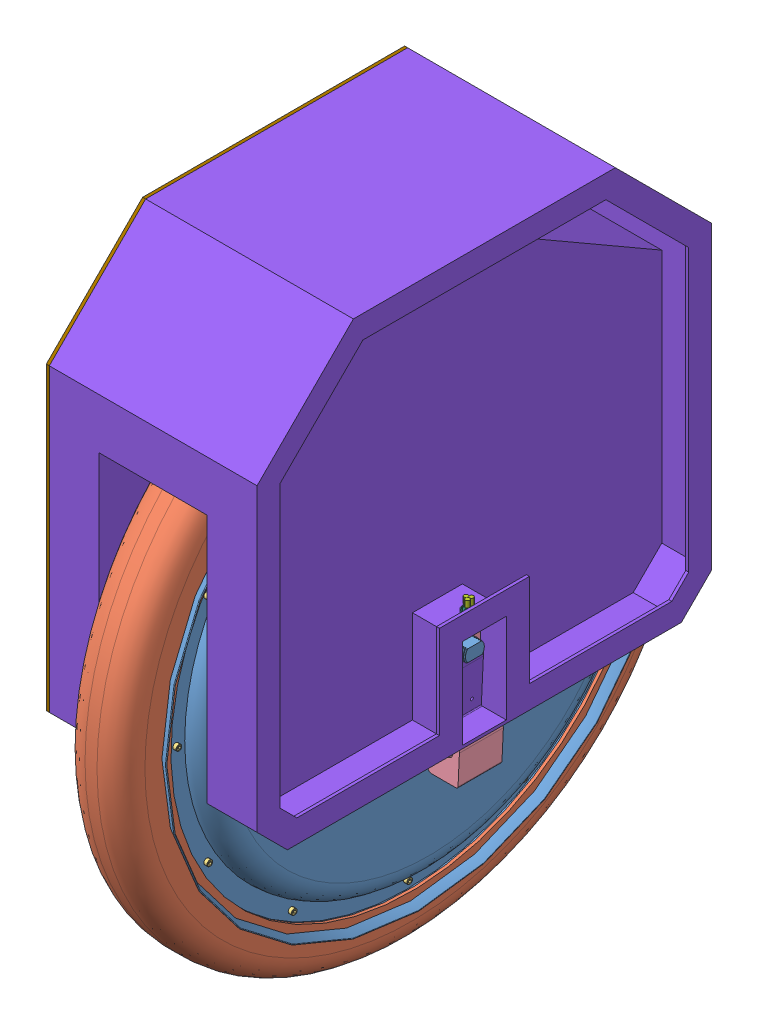
SolidWorks assembly euc0.5, configuration Default. Lengths in mm.
Overall size (364.75 810.04 810.04).
40 component instances, 14 part files, 56 mates.
Components (placement in the parent):
- wheel-1: wheel [Default] at origin size (217.51 810.04 810.04)
  - motor-1: motor [Default] at origin size (188.73 505.83 505.83)
  - tyre-1: tyre [Default] at (-29.8207 0 0) x (1 0 0) z (0 0.587098 0.809516) size (60 580 580)
  - socket head cap screw_ai-1: socket head cap screw_ai [HX-SHCS 0.138-40x0.188x0.188-N] at (29.5052 231 0) x (-1 0 0) z (0 0 -1) size (8.28 5.74 5.74)
  - socket head cap screw_ai-2: socket head cap screw_ai [HX-SHCS 0.138-40x0.188x0.188-N] at (29.5052 200.0519 -115.5) x (-1 0 0) z (0 -0.5 -0.866025) size (8.28 5.74 5.74)
  - socket head cap screw_ai-3: socket head cap screw_ai [HX-SHCS 0.138-40x0.188x0.188-N] at (29.5052 200.0519 115.5) x (-1 0 0) z (0 0.5 -0.866025) size (8.28 5.74 5.74)
  - socket head cap screw_ai-4: socket head cap screw_ai [HX-SHCS 0.138-40x0.188x0.188-N] at (29.5052 115.5 200.0519) x (-1 0 0) z (0 0.866025 -0.5) size (8.28 5.74 5.74)
  - socket head cap screw_ai-5: socket head cap screw_ai [HX-SHCS 0.138-40x0.188x0.188-N] at (29.5052 0 231) x (-1 0 0) z (0 1 0) size (8.28 5.74 5.74)
  - socket head cap screw_ai-6: socket head cap screw_ai [HX-SHCS 0.138-40x0.188x0.188-N] at (29.5052 -115.5 200.0519) x (-1 0 0) z (0 0.866025 0.5) size (8.28 5.74 5.74)
  - socket head cap screw_ai-7: socket head cap screw_ai [HX-SHCS 0.138-40x0.188x0.188-N] at (29.5052 -200.0519 115.5) x (-1 0 0) z (0 0.5 0.866025) size (8.28 5.74 5.74)
  - socket head cap screw_ai-8: socket head cap screw_ai [HX-SHCS 0.138-40x0.188x0.188-N] at (29.5052 -231 0) x (-1 0 0) z (0 0 1) size (8.28 5.74 5.74)
  - socket head cap screw_ai-9: socket head cap screw_ai [HX-SHCS 0.138-40x0.188x0.188-N] at (29.5052 -200.0519 -115.5) x (-1 0 0) z (0 -0.5 0.866025) size (8.28 5.74 5.74)
  - socket head cap screw_ai-10: socket head cap screw_ai [HX-SHCS 0.138-40x0.188x0.188-N] at (29.5052 -115.5 -200.0519) x (-1 0 0) z (0 -0.866025 0.5) size (8.28 5.74 5.74)
  - socket head cap screw_ai-11: socket head cap screw_ai [HX-SHCS 0.138-40x0.188x0.188-N] at (29.5052 0 -231) x (-1 0 0) z (0 -1 0) size (8.28 5.74 5.74)
  - socket head cap screw_ai-12: socket head cap screw_ai [HX-SHCS 0.138-40x0.188x0.188-N] at (29.5052 115.5 -200.0519) x (-1 0 0) z (0 -0.866025 -0.5) size (8.28 5.74 5.74)
  - socket head cap screw_ai-13: socket head cap screw_ai [HX-SHCS 0.138-40x0.188x0.188-N] at (-29.5052 231 0) size (8.28 5.74 5.74)
  - socket head cap screw_ai-14: socket head cap screw_ai [HX-SHCS 0.138-40x0.188x0.188-N] at (-29.5052 200.0519 -115.5) x (1 0 0) z (0 0.5 0.866025) size (8.28 5.74 5.74)
  - socket head cap screw_ai-15: socket head cap screw_ai [HX-SHCS 0.138-40x0.188x0.188-N] at (-29.5052 200.0519 115.5) x (1 0 0) z (0 -0.5 0.866025) size (8.28 5.74 5.74)
  - socket head cap screw_ai-16: socket head cap screw_ai [HX-SHCS 0.138-40x0.188x0.188-N] at (-29.5052 115.5 200.0519) x (1 0 0) z (0 -0.866025 0.5) size (8.28 5.74 5.74)
  - socket head cap screw_ai-17: socket head cap screw_ai [HX-SHCS 0.138-40x0.188x0.188-N] at (-29.5052 0 231) x (1 0 0) z (0 -1 0) size (8.28 5.74 5.74)
  - socket head cap screw_ai-18: socket head cap screw_ai [HX-SHCS 0.138-40x0.188x0.188-N] at (-29.5052 -115.5 200.0519) x (1 0 0) z (0 -0.866025 -0.5) size (8.28 5.74 5.74)
  - socket head cap screw_ai-19: socket head cap screw_ai [HX-SHCS 0.138-40x0.188x0.188-N] at (-29.5052 -200.0519 115.5) x (1 0 0) z (0 -0.5 -0.866025) size (8.28 5.74 5.74)
  - socket head cap screw_ai-20: socket head cap screw_ai [HX-SHCS 0.138-40x0.188x0.188-N] at (-29.5052 -231 0) x (1 0 0) z (0 0 -1) size (8.28 5.74 5.74)
  - socket head cap screw_ai-21: socket head cap screw_ai [HX-SHCS 0.138-40x0.188x0.188-N] at (-29.5052 -200.0519 -115.5) x (1 0 0) z (0 0.5 -0.866025) size (8.28 5.74 5.74)
  - socket head cap screw_ai-22: socket head cap screw_ai [HX-SHCS 0.138-40x0.188x0.188-N] at (-29.5052 -115.5 -200.0519) x (1 0 0) z (0 0.866025 -0.5) size (8.28 5.74 5.74)
  - socket head cap screw_ai-23: socket head cap screw_ai [HX-SHCS 0.138-40x0.188x0.188-N] at (-29.5052 0 -231) x (1 0 0) z (0 1 0) size (8.28 5.74 5.74)
  - socket head cap screw_ai-24: socket head cap screw_ai [HX-SHCS 0.138-40x0.188x0.188-N] at (-29.5052 115.5 -200.0519) x (1 0 0) z (0 0.866025 0.5) size (8.28 5.74 5.74)
  - pedal hanger1-1: pedal hanger1 [Default] at (128.9328 -140.4403 -75.0082) x (0.997537 -0.070149 0) z (-0.006861 -0.09757 0.995205) size (54.31 133.41 56.48)
  - pedal hanger2-1: pedal hanger2 [Default] at (-128.9328 -140.4403 75.0082) x (-0.997537 -0.070149 0) z (0.006861 -0.09757 -0.995205) size (54.31 133.41 56.48)
- mt60 fem-1: mt60 fem [Default] at (85.5155 -2.714 -4.2673) x (0 1 0) z (0.866025 0 -0.5) size (29 12 12.94)
  - Мама^mt60 fem-1: Мама^mt60 fem [По умолчанию] at (18.214 0 0) x (0 0 -1) z (1 0 0) size (12.94 12 20) (virtual)
  - Колпачек 2^mt60 fem-1: Колпачек 2^mt60 fem [По умолчанию] at (35.714 0 0) x (0 0 -1) z (1 0 0) size (12.94 12 13) (hidden, virtual)
  - Деталь11^mt60 fem-1: Деталь11^mt60 fem [По умолчанию] at (44.714 0 0) x (0 0 -1) z (1 0 0) size (8 7.46 6.5) (virtual)
- Battery-1: Battery [Default] at (75 -47.6654 124.2759) x (0 0 -1) z (1 0 0) size (162 240 36) (hidden)
- Battery2-1: Battery2 [Default] at (75 -56.177 -111.8756) x (0 0 -1) z (1 0 0) size (162 260 36) (hidden)
- Battery3-1: Battery3 [Default] at (-206.3607 -72.6948 -163.7053) x (0 0 -1) z (1 0 0) size (162 260 36) (hidden)
- Battery4-1: Battery4 [Default] at (-186.6008 -70.2528 81.2406) x (0 0 -1) z (1 0 0) size (162 260 36) (hidden)
- Chassis^euc0.5-5: Chassis^euc0.5 [Default] at (48 0 0) x (0 0 -1) z (1 0 0) size (455.15 427.31 208) (virtual)
- Lid^euc0.5-3: Lid^euc0.5 [Default] at (104 0 0) x (0 0 -1) z (1 0 0) size (455.15 427.31 3) (hidden, virtual)
- Lid^euc0.5-4: Lid^euc0.5 [Default] at (-104 0 0) x (0 0 1) z (-1 0 0) size (455.15 427.31 3) (virtual)
Mates (geometry in assembly coordinates):
- Parallel1: parallel anti-aligned: plane of Chassis-1/Internal chassis-1 through (0 28 0) normal (0 1 0); plane of mt60 fem-1/Copy of Мама^mt60 fem-1 through (90.0311 15.5 3.5538) normal (0 -1 0)
- Parallel2: parallel aligned: plane of Chassis-1/Internal chassis-1 through (57 28 288) normal (1 0 0); plane of mt60 fem-1/Copy of Мама^mt60 fem-1 through (93 29 3.5538) normal (1 0 0)
- Coincident3: coincident anti-aligned: plane of Chassis-1/Internal chassis-1 through (93 7.266 3.5) normal (-1 0 0); plane of mt60 fem-1/Copy of Мама^mt60 fem-1 through (93 29 3.5538) normal (1 0 0)
- Coincident4: coincident anti-aligned: plane of Chassis-1/Internal chassis-1 through (82.4378 7.266 2.5981) normal (0.5 0 -0.866025); plane of mt60 fem-1/Copy of Мама^mt60 fem-1 through (82.4845 29 2.625) normal (-0.5 0 0.866025)
- Coincident5: coincident aligned: plane of Chassis-1/Internal chassis-1 through (100 25 0) normal (0 -1 0); plane of mt60 fem-1/Copy of Мама^mt60 fem-1 through (83.9689 25 0.0538) normal (0 -1 0)
- Coincident18: coincident anti-aligned: plane of Chassis-1/Internal chassis-1 through (57 28 288) normal (1 0 0); plane of Battery1-1 through (57 187.8877 190.3024) normal (-1 0 0)
- Coincident23: coincident anti-aligned: plane of Chassis-1/Internal chassis-1 through (57 28 288) normal (1 0 0); plane of Battery2-2 through (57 212.7697 -24.9641) normal (-1 0 0)
- Parallel5: parallel aligned: plane of Chassis-1/Internal chassis-1 through (0 28 0) normal (0 1 0); plane of Battery1-1 through (75 187.8877 109.3024) normal (0 1 0)
- Parallel6: parallel aligned: plane of Chassis-1/Internal chassis-1 through (0 28 0) normal (0 1 0); plane of Battery2-2 through (75 212.7697 -105.9641) normal (0 1 0)
- InPlace2: in place: plane of wheel-1/motor-1 through (57 28 288) normal (1 0 0); plane of ? through (57 0 0) normal (1 0 0); moOrthogonalPlaneRef_w of wheel-1/motor-1 through (57 28 288) normal (1 0 0); plane of ? through (57 0 0) normal (0 1 0); plane of wheel-1/motor-1 through (57 28 288) normal (1 0 0); plane of ? through (57 0 0) normal (0 0 -1); plane of wheel-1/motor-1 through (57 28 288) normal (1 0 0); unknown of ?
- Coincident26: coincident aligned: plane of ?; plane of ?
- Coincident27: coincident aligned: moOrthogonalPlaneRef_w of Chassis-1/Internal chassis-1 through (57 0 0) normal (0 1 0); plane of Lid^euc0.2-2 through (57 0 0) normal (0 1 0)
- Coincident28: coincident anti-aligned: moOrthogonalPlaneRef_w of Chassis-1/Internal chassis-1 through (57 0 0) normal (0 0 1); plane of Lid^euc0.2-2 through (57 0 0) normal (0 0 -1)
- InPlace3: in place: plane of wheel-1/motor-1 through (0 303.0294 0) normal (0 1 0); plane of ? through (0 303.0294 0) normal (0 1 0); plane of wheel-1/motor-1 through (0 303.0294 0) normal (0 1 0); plane of ? through (0 303.0294 0) normal (0 0 -1); plane of wheel-1/motor-1 through (0 303.0294 0) normal (0 1 0); plane of ? through (0 303.0294 0) normal (1 0 0); plane of wheel-1/motor-1 through (0 303.0294 0) normal (0 1 0); unknown of ?
- Coincident1482: coincident aligned: plane of ?; plane of ?
- Coincident1483: coincident aligned: moOrthogonalPlaneRef_w of top chassis^euc0.2-1 through (0 303.0294 0) normal (0 0 -1); plane of Pcb plate^euc0.2-1 through (0 303.0294 0) normal (0 0 -1)
- Coincident1484: coincident anti-aligned: moOrthogonalPlaneRef_w of top chassis^euc0.2-1 through (0 303.0294 0) normal (-1 0 0); plane of Pcb plate^euc0.2-1 through (0 303.0294 0) normal (1 0 0)
- Coincident1488: coincident anti-aligned: plane of Pcb plate^euc0.2-1 through (-24 312.0294 76) normal (0 1 0); plane of pcb^euc0.2-1 through (0 312.0294 0) normal (0 -1 0)
- Coincident1489: coincident aligned: plane of Pcb plate^euc0.2-1 through (-40 307.0294 80) normal (0 0 1); plane of pcb^euc0.2-1 through (-28 315.0294 80) normal (0 0 1)
- Coincident1490: coincident anti-aligned: plane of Pcb plate^euc0.2-1 through (28 315.0294 -80) normal (-1 0 0); plane of pcb^euc0.2-1 through (28 315.0294 80) normal (1 0 0)
- Coincident1491: coincident anti-aligned: plane of Chassis-1/Internal chassis-1 through (57 28 288) normal (1 0 0); plane of Battery-2 through (57 183.6915 -26.6601) normal (-1 0 0)
- InPlace4: in place: plane of wheel-1/motor-1 through (104 0 237.8048) normal (1 0 0); plane of Lid^euc0.5-3 through (104 0 0) normal (1 0 0); plane of wheel-1/motor-1 through (104 0 237.8048) normal (1 0 0); plane of Lid^euc0.5-3 through (104 0 0) normal (0 1 0); plane of wheel-1/motor-1 through (104 0 237.8048) normal (1 0 0); plane of Lid^euc0.5-3 through (104 0 0) normal (0 0 -1); plane of wheel-1/motor-1 through (104 0 237.8048) normal (1 0 0); unknown of Lid^euc0.5-3
- Coincident1493: coincident aligned: plane of ?; plane of ?
- Coincident1494: coincident aligned: moOrthogonalPlaneRef_w of Chassis^euc0.3-3 through (104 0 0) normal (0 1 0); plane of Lid^euc0.3-1 through (104 0 0) normal (0 1 0)
- Coincident1495: coincident anti-aligned: moOrthogonalPlaneRef_w of Chassis^euc0.3-3 through (104 0 0) normal (0 0 1); plane of Lid^euc0.3-1 through (104 0 0) normal (0 0 -1)
- Coincident1496: coincident anti-aligned: plane of Chassis^euc0.3-3 through (-104 0 237.8048) normal (-1 0 0); plane of Lid-2 through (-104 0 0) normal (1 0 0)
- Coincident1497: coincident aligned: plane of Chassis^euc0.3-3 through (-266.8954 375.6488 120.8782) normal (0 1 0); plane of Lid-2 through (-107 375.6488 120.8782) normal (0 1 0)
- Coincident1498: coincident aligned: plane of Chassis^euc0.3-3 through (0 0 237.8048) normal (0 0 1); plane of Lid-2 through (-107 -38.5515 237.8048) normal (0 0 1)
- Coincident1499: coincident anti-aligned: plane of Chassis^euc0.3-3 through (57 0 0) normal (1 0 0); plane of Battery-1 through (57 192.3346 205.2759) normal (-1 0 0)
- Coincident1500: coincident anti-aligned: plane of Chassis^euc0.3-3 through (57 0 0) normal (1 0 0); plane of Battery2-1 through (57 203.823 -30.8756) normal (-1 0 0)
- Coincident1501: coincident anti-aligned: plane of Chassis^euc0.3-3 through (-57 0 0) normal (-1 0 0); plane of Battery3-1 through (-188.3607 187.3052 -82.7053) normal (1 0 0)
- Coincident1502: coincident anti-aligned: plane of Chassis^euc0.3-3 through (-57 0 0) normal (-1 0 0); plane of Battery4-1 through (-168.6008 189.7472 162.2406) normal (1 0 0)
- Parallel8: parallel aligned: plane of wheel-1/motor-1 through (48 0 0) normal (1 0 0); plane of Chassis^euc0.5-4 through (128.9328 -140.4403 22) normal (1 0 0)
- Coincident1509: coincident: unknown of wheel-1
- Coincident1510: coincident: unknown of wheel-1
- Parallel9: parallel aligned: plane of wheel-1/pedal hanger1-1 through (74 -75.003 22) normal (0 0 1)
- InPlace6: in place: plane of ? through (0 0 0) normal (1 0 0); plane of ? through (0 0 0) normal (1 0 0); plane of ? through (0 0 0) normal (1 0 0); plane of ? through (0 0 0) normal (0 1 0); plane of ? through (0 0 0) normal (1 0 0); plane of ? through (0 0 0) normal (0 0 -1); plane of wheel-1/motor-1 through (48 0 0) normal (1 0 0); unknown of Chassis^euc0.5-5
- Coincident1512: coincident aligned: plane of ?; plane of ?
- Coincident1513: coincident aligned: moOrthogonalPlaneRef_w of wheel-1/motor-1 through (48 0 0) normal (0 1 0); plane of Chassis^euc0.5-5 through (48 0 0) normal (0 1 0)
- Coincident1514: coincident anti-aligned: moOrthogonalPlaneRef_w of wheel-1/motor-1 through (48 0 0) normal (0 0 1); plane of Chassis^euc0.5-5 through (48 0 0) normal (0 0 -1)
- Coincident1515: coincident: unknown of wheel-1
- Parallel11: parallel aligned: plane of wheel-1/motor-1 through (48 0 0) normal (1 0 0)
- InPlace7: in place: plane of Chassis^euc0.5-5 through (57 0 0) normal (1 0 0); plane of ? through (57 0 0) normal (1 0 0); plane of Chassis^euc0.5-5 through (57 0 0) normal (1 0 0); plane of ? through (57 0 0) normal (0 1 0); plane of Chassis^euc0.5-5 through (57 0 0) normal (1 0 0); plane of ? through (57 0 0) normal (0 0 -1); plane of Chassis^euc0.5-5 through (57 0 0) normal (1 0 0); unknown of ?
- Coincident1517: coincident aligned: plane of ?; plane of ?
- Coincident1518: coincident aligned: moOrthogonalPlaneRef_w of Chassis^euc0.5-5 through (57 0 0) normal (0 1 0); plane of Lid^euc0.5-1 through (57 0 0) normal (0 1 0)
- Coincident1519: coincident anti-aligned: moOrthogonalPlaneRef_w of Chassis^euc0.5-5 through (57 0 0) normal (0 0 1); plane of Lid^euc0.5-1 through (57 0 0) normal (0 0 -1)
- Coincident1520: coincident anti-aligned: plane of Chassis^euc0.5-5 through (-104 25 25) normal (-1 0 0); plane of Lid^euc0.5-2 through (-104 0 0) normal (1 0 0)
- Coincident1521: coincident aligned: plane of Chassis^euc0.5-5 through (57 -37.635 227.577) normal (0 0 1); plane of Lid^euc0.5-2 through (-107 -37.635 227.577) normal (0 0 1)
- Coincident1522: coincident aligned: plane of Chassis^euc0.5-5 through (-248.0003 359.3102 131.1444) normal (0 1 0); plane of Lid^euc0.5-2 through (-107 359.3102 131.1444) normal (0 1 0)
- InPlace8: in place: plane of Chassis^euc0.5-5 through (104 25 25) normal (1 0 0); plane of Lid^euc0.5-3 through (104 0 0) normal (1 0 0); plane of Chassis^euc0.5-5 through (104 25 25) normal (1 0 0); plane of Lid^euc0.5-3 through (104 0 0) normal (0 1 0); plane of Chassis^euc0.5-5 through (104 25 25) normal (1 0 0); plane of Lid^euc0.5-3 through (104 0 0) normal (0 0 -1); plane of Chassis^euc0.5-5 through (104 25 25) normal (1 0 0); unknown of Lid^euc0.5-3
- Coincident1523: coincident aligned: plane of ?; plane of ?
- Coincident1524: coincident aligned: moOrthogonalPlaneRef_w of Chassis^euc0.5-5 through (104 0 0) normal (0 1 0); plane of Lid^euc0.5-3 through (104 0 0) normal (0 1 0)
- Coincident1525: coincident anti-aligned: moOrthogonalPlaneRef_w of Chassis^euc0.5-5 through (104 0 0) normal (0 0 1); plane of Lid^euc0.5-3 through (104 0 0) normal (0 0 -1)
- Coincident1526: coincident anti-aligned: plane of Chassis^euc0.5-5 through (-104 25 25) normal (-1 0 0); plane of Lid^euc0.5-4 through (-104 0 0) normal (1 0 0)
- Coincident1527: coincident aligned: plane of Chassis^euc0.5-5 through (57 -37.635 227.577) normal (0 0 1); plane of Lid^euc0.5-4 through (-107 -37.635 227.577) normal (0 0 1)
- Coincident1528: coincident aligned: plane of Chassis^euc0.5-5 through (-248.0003 359.3102 131.1444) normal (0 1 0); plane of Lid^euc0.5-4 through (-107 359.3102 131.1444) normal (0 1 0)
